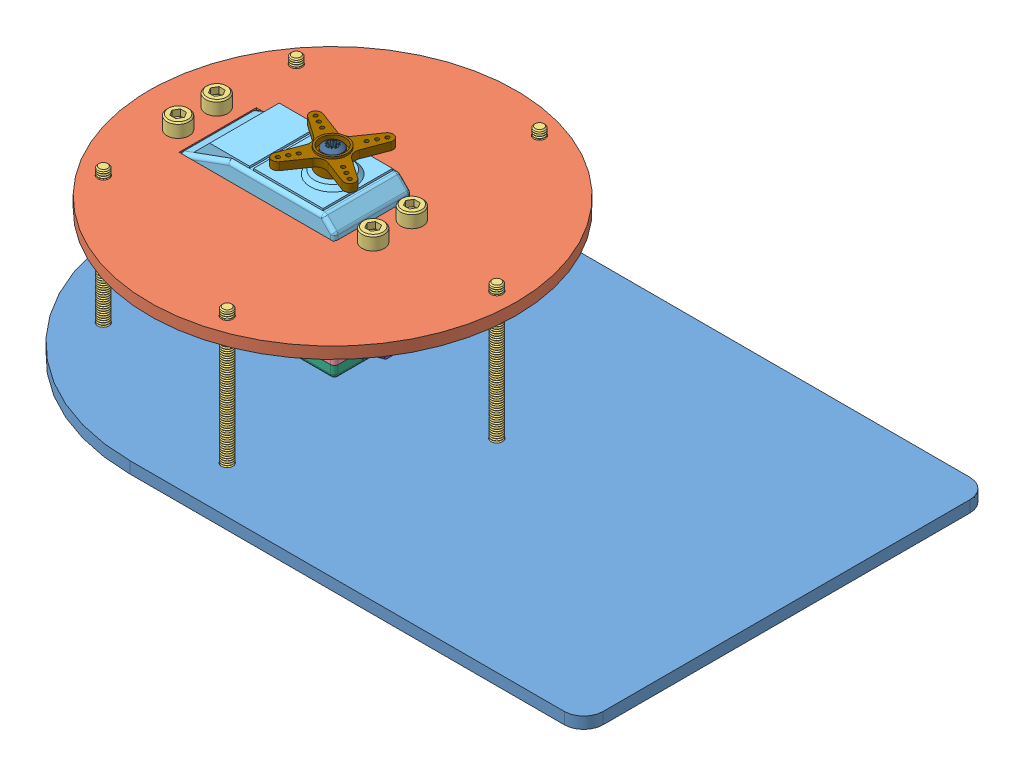
SolidWorks assembly robot_esamble_1_v0, configuration Predeterminado. Lengths in mm.
Overall size (170 50.72 105).
19 component instances, 10 part files, 29 mates.
Components (placement in the parent):
- A_pieza_arm_robot_v0-1: A_pieza_arm_robot_v0 [Predeterminado] x (0 0 -1) z (0 1 0) size (105 170 3)
- B_pieza_arm_robot_v0-1: B_pieza_arm_robot_v0 [Predeterminado] at (0 33 0) x (-1 0 0) z (0 1 0) size (95 95 3)
- socket head cap screw_ai-1: socket head cap screw_ai [HX-SHCS 0.112-48x1.5x1.5-S] at (13.1332 -2.8448 -40.4199) x (0 1 0) z (0 0 1) size (40.94 4.65 4.65)
- socket head cap screw_ai-2: socket head cap screw_ai [HX-SHCS 0.112-48x1.5x1.5-S] at (-34.3832 -2.8448 -24.9809) x (0 1 0) z (0 0 1) size (40.94 4.65 4.65)
- socket head cap screw_ai-3: socket head cap screw_ai [HX-SHCS 0.112-48x1.5x1.5-S] at (-34.3832 -2.8448 24.9809) x (0 1 0) z (0 0 1) size (40.94 4.65 4.65)
- socket head cap screw_ai-4: socket head cap screw_ai [HX-SHCS 0.112-48x1.5x1.5-S] at (13.1332 -2.8448 40.4199) x (0 1 0) z (0 0 1) size (40.94 4.65 4.65)
- socket head cap screw_ai-5: socket head cap screw_ai [HX-SHCS 0.112-48x1.5x1.5-S] at (42.5 -2.8448 0) x (0 1 0) z (0 0 1) size (40.94 4.65 4.65)
- Servomoteur Futuba S3003-4: Servomoteur Futuba S3003 [Défaut] at (-9.3643 24.2642 -40.4) size (55.5 42.98 32.41)
  - Boitier-1: Boitier [Défaut] at (8.3252 -16.2642 40.4) size (40.4 21 20)
  - Couvercle supérieure-1: Couvercle supérieure [Défaut] at (9.3643 6.7358 40.4) size (55.5 13 20)
  - Couvercle inférieure-1: Couvercle inférieure [Défaut] at (4.9957 -19.3642 40.4) size (40.4 3.1 20)
  - Axe-1: Axe [Défaut] at (9.3643 15.2358 40.4) size (5 16 5)
  - Passe fil-1: Passe fil [Défaut] at (17.8143 -15.2642 40.4) x (0 0 -1) z (1 0 0) size (7 5 7.5)
  - Palonnier-1: Palonnier [Défaut] at (9.3643 21.7358 40.4) x (0.465117 0 -0.885249) z (0 1 0) size (24 24 5)
  - Vis CBL Z, M 2.5 - 5-1: Vis CBL Z, M 2.5 - 5 [Défaut] at (9.3643 21.7358 40.4) x (0.991239 0 0.132079) z (0 1 0) size (5 5 6.88)
- socket head cap screw_ai-22: socket head cap screw_ai [HX-SHCS 0.138-40x0.3125x0.3125-S] at (15.5 39.5052 5) x (0 -1 0) z (0 0 1) size (11.44 5.74 5.74)
- socket head cap screw_ai-23: socket head cap screw_ai [HX-SHCS 0.138-40x0.3125x0.3125-S] at (15.5 39.5052 -5) x (0 -1 0) z (0 0 1) size (11.44 5.74 5.74)
- socket head cap screw_ai-24: socket head cap screw_ai [HX-SHCS 0.138-40x0.3125x0.3125-S] at (-35 39.5052 5) x (0 -1 0) z (0 0 1) size (11.44 5.74 5.74)
- socket head cap screw_ai-25: socket head cap screw_ai [HX-SHCS 0.138-40x0.3125x0.3125-S] at (-35 39.5052 -5) x (0 -1 0) z (0 0 1) size (11.44 5.74 5.74)
Mates (geometry in assembly coordinates):
- Coincidente1: coincident anti-aligned: plane of A_pieza_arm_robot_v0-1 through (0 0 0) normal (0 -1 0)
- Coincidente2: coincident anti-aligned: plane of A_pieza_arm_robot_v0-1 through (0 0 0) normal (0 0 -1)
- Coincidente3: coincident anti-aligned: plane of A_pieza_arm_robot_v0-1 through (0 0 0) normal (-1 0 0)
- Distancia1: distance = 30 mm anti-aligned: plane of B_pieza_arm_robot_v0-1 through (0 33 0) normal (0 -1 0); plane of A_pieza_arm_robot_v0-1 through (0 3 0) normal (0 1 0)
- Concéntrica1: concentric aligned: cylinder of A_pieza_arm_robot_v0-1 through (42.5 0 0) axis (0 1 0) radius 1.5; cylinder of B_pieza_arm_robot_v0-1 through (42.5 33 0) axis (0 1 0) radius 1.5
- Concéntrica2: concentric aligned: cylinder of A_pieza_arm_robot_v0-1 through (-34.3832 0 24.9809) axis (0 1 0) radius 1.5; cylinder of B_pieza_arm_robot_v0-1 through (-34.3832 33 24.9809) axis (0 1 0) radius 1.5
- Concéntrica3: concentric aligned: cylinder of B_pieza_arm_robot_v0-1 through (0 36 0) axis (0 -1 0) radius 47.5; cylinder of H_pieza_arm_robot_v0-1 through (0 45 0) axis (0 -1 0) radius 47.5
- Distancia2: distance = 6 mm anti-aligned: plane of B_pieza_arm_robot_v0-1 through (0 36 0) normal (0 1 0); plane of H_pieza_arm_robot_v0-1 through (0 42 0) normal (0 -1 0)
- Concéntrica21: concentric anti-aligned: cylinder of A_pieza_arm_robot_v0-1 through (13.1332 0 -40.4199) axis (0 1 0) radius 1.5; cylinder of socket head cap screw_ai-1 through (13.1332 -34.5948 -40.4199) axis (0 -1 0) radius 2.3241
- Coincidente29: coincident anti-aligned: plane of A_pieza_arm_robot_v0-1 through (0 0 0) normal (0 -1 0); plane of socket head cap screw_ai-1 through (10.8091 0 -40.4199) normal (0 1 0)
- Concéntrica22: concentric anti-aligned: cylinder of A_pieza_arm_robot_v0-1 through (-34.3832 0 -24.9809) axis (0 1 0) radius 1.5; cylinder of socket head cap screw_ai-2 through (-34.3832 -34.5948 -24.9809) axis (0 -1 0) radius 2.3241
- Coincidente30: coincident anti-aligned: plane of A_pieza_arm_robot_v0-1 through (0 0 0) normal (0 -1 0); plane of socket head cap screw_ai-2 through (-36.7073 0 -24.9809) normal (0 1 0)
- Concéntrica23: concentric anti-aligned: cylinder of A_pieza_arm_robot_v0-1 through (-34.3832 0 24.9809) axis (0 1 0) radius 1.5; cylinder of socket head cap screw_ai-3 through (-34.3832 -34.5948 24.9809) axis (0 -1 0) radius 2.3241
- Coincidente31: coincident anti-aligned: plane of A_pieza_arm_robot_v0-1 through (0 0 0) normal (0 -1 0); plane of socket head cap screw_ai-3 through (-36.7073 0 24.9809) normal (0 1 0)
- Concéntrica24: concentric anti-aligned: cylinder of A_pieza_arm_robot_v0-1 through (13.1332 0 40.4199) axis (0 1 0) radius 1.5; cylinder of socket head cap screw_ai-4 through (13.1332 -34.5948 40.4199) axis (0 -1 0) radius 2.3241
- Coincidente32: coincident anti-aligned: plane of A_pieza_arm_robot_v0-1 through (0 0 0) normal (0 -1 0); plane of socket head cap screw_ai-4 through (10.8091 0 40.4199) normal (0 1 0)
- Concéntrica25: concentric anti-aligned: cylinder of A_pieza_arm_robot_v0-1 through (42.5 0 0) axis (0 1 0) radius 1.5; cylinder of socket head cap screw_ai-5 through (42.5 -34.5948 0) axis (0 -1 0) radius 2.3241
- Coincidente33: coincident anti-aligned: plane of A_pieza_arm_robot_v0-1 through (0 0 0) normal (0 -1 0); plane of socket head cap screw_ai-5 through (40.1759 0 0) normal (0 1 0)
- Coincidente34: coincident anti-aligned: plane of B_pieza_arm_robot_v0-1 through (0 33 0) normal (0 -1 0); plane of Servomoteur Futuba S3003-4/Couvercle supérieure-1 through (-35 33 -5) normal (0 1 0)
- Concéntrica28: concentric anti-aligned: cylinder of B_pieza_arm_robot_v0-1 through (-35 33 5) axis (0 1 0) radius 2; cylinder of Servomoteur Futuba S3003-4/Couvercle supérieure-1 through (-35 33 5) axis (0 -1 0) radius 2
- Concéntrica29: concentric anti-aligned: cylinder of B_pieza_arm_robot_v0-1 through (-35 33 -5) axis (0 1 0) radius 2; cylinder of Servomoteur Futuba S3003-4/Couvercle supérieure-1 through (-35 33 -5) axis (0 -1 0) radius 2
- Concéntrica45: concentric aligned: cylinder of B_pieza_arm_robot_v0-1 through (15.5 33 5) axis (0 1 0) radius 2; cylinder of socket head cap screw_ai-22 through (15.5 71.2552 5) axis (0 1 0) radius 2.8702
- Coincidente51: coincident anti-aligned: plane of B_pieza_arm_robot_v0-1 through (0 36 0) normal (0 1 0); plane of socket head cap screw_ai-22 through (18.3702 36 5) normal (0 -1 0)
- Concéntrica46: concentric aligned: cylinder of B_pieza_arm_robot_v0-1 through (15.5 33 -5) axis (0 1 0) radius 2; cylinder of socket head cap screw_ai-23 through (15.5 71.2552 -5) axis (0 1 0) radius 2.8702
- Coincidente52: coincident anti-aligned: plane of B_pieza_arm_robot_v0-1 through (0 36 0) normal (0 1 0); plane of socket head cap screw_ai-23 through (18.3702 36 -5) normal (0 -1 0)
- Concéntrica47: concentric aligned: cylinder of B_pieza_arm_robot_v0-1 through (-35 33 5) axis (0 1 0) radius 2; cylinder of socket head cap screw_ai-24 through (-35 71.2552 5) axis (0 1 0) radius 2.8702
- Coincidente53: coincident anti-aligned: plane of B_pieza_arm_robot_v0-1 through (0 36 0) normal (0 1 0); plane of socket head cap screw_ai-24 through (-32.1298 36 5) normal (0 -1 0)
- Concéntrica48: concentric aligned: cylinder of B_pieza_arm_robot_v0-1 through (-35 33 -5) axis (0 1 0) radius 2; cylinder of socket head cap screw_ai-25 through (-35 71.2552 -5) axis (0 1 0) radius 2.8702
- Coincidente54: coincident anti-aligned: plane of B_pieza_arm_robot_v0-1 through (0 36 0) normal (0 1 0); plane of socket head cap screw_ai-25 through (-32.1298 36 -5) normal (0 -1 0)
